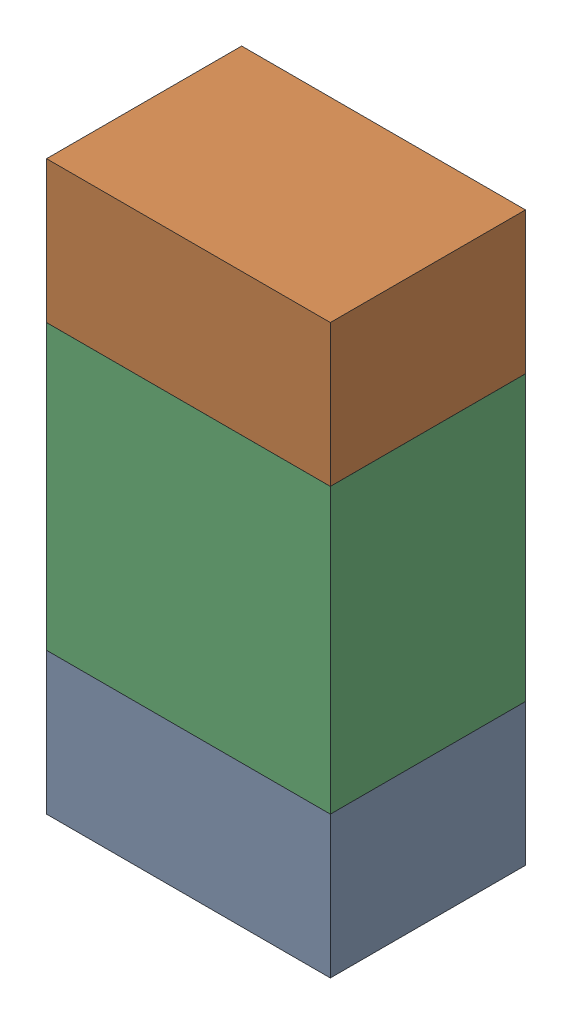
SolidWorks assembly R64, configuration ﾃﾞﾌｫﾙﾄ. Lengths in mm.
Overall size (0.8 1.6 0.55).
6 component instances, 2 part files, 0 mates.
Components (placement in the parent):
- 689261784-1: 689261784 [ﾃﾞﾌｫﾙﾄ] at (78.5001 35.1501 -1.7503) size (0.8 0.4 0.55)
  - Extruded_34-1: Extruded_34 [ﾃﾞﾌｫﾙﾄ] at origin size (0.8 0.4 0.55)
- 689261784-2: 689261784 [ﾃﾞﾌｫﾙﾄ] at (78.5001 36.3501 -1.7503) size (0.8 0.4 0.55)
  - Extruded_34-1: Extruded_34 [ﾃﾞﾌｫﾙﾄ] at origin size (0.8 0.4 0.55)
- 689261648-1: 689261648 [ﾃﾞﾌｫﾙﾄ] at (78.5001 35.75 -1.7503) size (0.8 0.8 0.55)
  - Extruded_33-1: Extruded_33 [ﾃﾞﾌｫﾙﾄ] at origin size (0.8 0.8 0.55)
